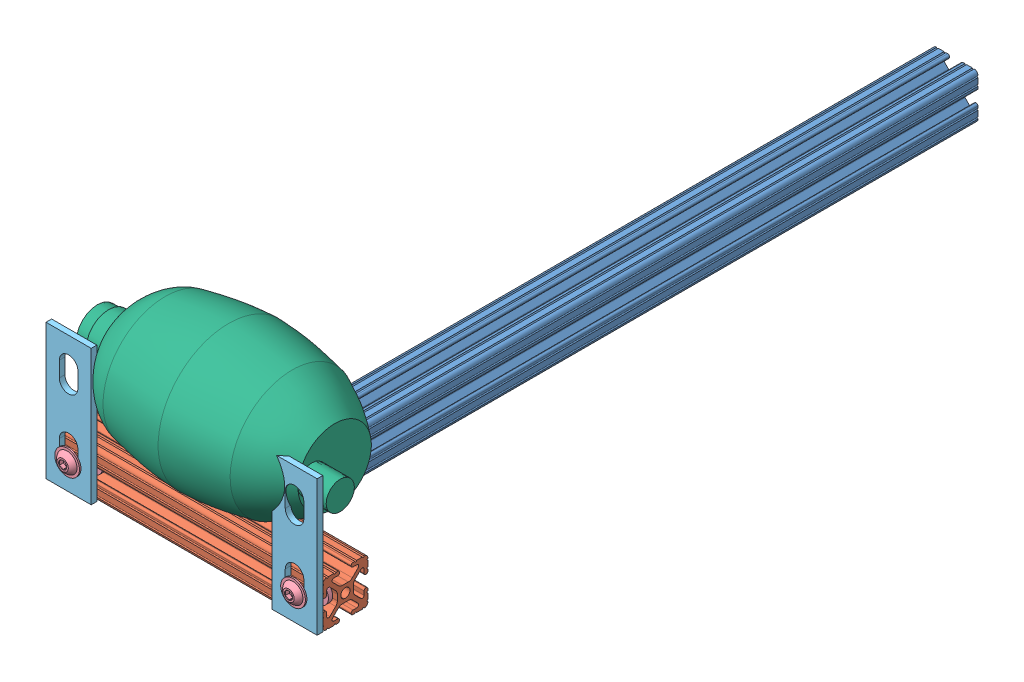
SolidWorks assembly FrameSubAssembly, configuration Default. Lengths in mm.
Overall size (154.3 103.19 450.85).
17 component instances, 6 part files, 17 mates.
Components (placement in the parent):
- 47065T435_ALUMINUM T-SLOTTED FRAMING EXTRUSION cylinder piece-1: 47065T435_ALUMINUM T-SLOTTED FRAMING EXTRUSION cylinder piece [47065T435] at (185.1645 185.311 414.0747) size (25.4 25.4 406.4)
- 47065T435_ALUMINUM T-SLOTTED FRAMING EXTRUSION cylinder piece2-1: 47065T435_ALUMINUM T-SLOTTED FRAMING EXTRUSION cylinder piece2 [47065T435] at (413.7645 185.311 528.3747) x (0 0 -1) z (1 0 0) size (25.4 25.4 152.4)
- BracketSubAssembly-1: BracketSubAssembly [Default] at (199.8275 170.0389 519.1358) x (1 0 0) z (0 1 0) size (33.74 33.74 22.23)
  - 47065T236_ALUMINUM T-SLOTTED FRAMING EXTRUSION-1: 47065T236_ALUMINUM T-SLOTTED FRAMING EXTRUSION [47065T236] at (-1.9629 3.4611 16.8596) size (25.4 25.4 22.23)
  - 47065T142_ALUMINUM T-SLOTTED FRAMING EXTRUSION-3: 47065T142_ALUMINUM T-SLOTTED FRAMING EXTRUSION [47065T142] at (2.8123 16.1611 16.8596) x (0 -1 0) z (0 0 1) size (25.4 16.7 13.87)
  - 47065T142_ALUMINUM T-SLOTTED FRAMING EXTRUSION-4: 47065T142_ALUMINUM T-SLOTTED FRAMING EXTRUSION [47065T142] at (10.7371 8.2363 16.8596) size (25.4 16.7 13.87)
- BracketSubAssembly-2: BracketSubAssembly [Default] at (170.5016 203.7582 519.1358) x (-1 0 0) z (0 -1 0) size (33.74 33.74 22.23)
  - 47065T236_ALUMINUM T-SLOTTED FRAMING EXTRUSION-1: 47065T236_ALUMINUM T-SLOTTED FRAMING EXTRUSION [47065T236] at (-1.9629 3.4611 16.8596) size (25.4 25.4 22.23)
  - 47065T142_ALUMINUM T-SLOTTED FRAMING EXTRUSION-3: 47065T142_ALUMINUM T-SLOTTED FRAMING EXTRUSION [47065T142] at (2.8123 16.1611 16.8596) x (0 -1 0) z (0 0 1) size (25.4 16.7 13.87)
  - 47065T142_ALUMINUM T-SLOTTED FRAMING EXTRUSION-4: 47065T142_ALUMINUM T-SLOTTED FRAMING EXTRUSION [47065T142] at (10.7371 8.2363 16.8596) size (25.4 16.7 13.87)
- BagBracketSubAssembly-1: BagBracketSubAssembly [Default] at (195.5559 169.3719 579.2774) x (0 0 -1) z (1 0 0) size (16.7 76.2 25.4)
  - 2312N340_FLAT-SURFACE MACHINE BRACKET-1: 2312N340_FLAT-SURFACE MACHINE BRACKET [2312N34] at (38.2027 41.3392 53.1086) x (0 1 0) z (0 0 1) size (76.2 3.17 25.4)
  - 47065T142_ALUMINUM T-SLOTTED FRAMING EXTRUSION-1: 47065T142_ALUMINUM T-SLOTTED FRAMING EXTRUSION [47065T142] at (35.0277 17.9839 53.1086) x (0 0 1) z (0 -1 0) size (25.4 16.7 13.87)
- BagBracketSubAssembly-2: BagBracketSubAssembly [Default] at (68.5559 169.3719 579.2774) x (0 0 -1) z (1 0 0) size (16.7 76.2 25.4)
  - 2312N340_FLAT-SURFACE MACHINE BRACKET-1: 2312N340_FLAT-SURFACE MACHINE BRACKET [2312N34] at (38.2027 41.3392 53.1086) x (0 1 0) z (0 0 1) size (76.2 3.17 25.4)
  - 47065T142_ALUMINUM T-SLOTTED FRAMING EXTRUSION-1: 47065T142_ALUMINUM T-SLOTTED FRAMING EXTRUSION [47065T142] at (35.0277 17.9839 53.1086) x (0 0 1) z (0 -1 0) size (25.4 16.7 13.87)
- Bag-2: Bag [Default] at (187.8568 236.111 520.3841) x (0 -1 0) z (1 0 0) size (79.38 79.38 149.22)
Mates (geometry in assembly coordinates):
- Coincident1: coincident aligned: line of 47065T435_ALUMINUM T-SLOTTED FRAMING EXTRUSION cylinder piece-1 through (185.1645 185.311 515.6747) axis (0 0 -1); line of 47065T435_ALUMINUM T-SLOTTED FRAMING EXTRUSION cylinder piece2-1 through (185.1645 185.311 525.798) axis (0 0 -1)
- Distance1: distance = 406.4 mm aligned: plane of 47065T435_ALUMINUM T-SLOTTED FRAMING EXTRUSION cylinder piece2-1 through (718.5645 191.6441 515.6747) normal (0 0 -1); plane of 47065T435_ALUMINUM T-SLOTTED FRAMING EXTRUSION cylinder piece-1 through (178.7481 175.9012 109.2747) normal (0 0 -1)
- Coincident3: coincident anti-aligned: plane of 47065T435_ALUMINUM T-SLOTTED FRAMING EXTRUSION cylinder piece-1 through (197.8645 191.6441 718.8747) normal (1 0 0); plane of BracketSubAssembly-1/47065T236_ALUMINUM T-SLOTTED FRAMING EXTRUSION-1 through (197.8645 198.011 515.6747) normal (-1 0 0)
- Coincident4: coincident anti-aligned: plane of 47065T435_ALUMINUM T-SLOTTED FRAMING EXTRUSION cylinder piece2-1 through (718.5645 191.6441 515.6747) normal (0 0 -1); plane of BracketSubAssembly-1/47065T236_ALUMINUM T-SLOTTED FRAMING EXTRUSION-1 through (223.2645 198.011 515.6747) normal (0 0 1)
- Coincident5: coincident aligned: plane of 47065T435_ALUMINUM T-SLOTTED FRAMING EXTRUSION cylinder piece-1 through (194.715 198.011 718.8747) normal (0 1 0); plane of BracketSubAssembly-1/47065T236_ALUMINUM T-SLOTTED FRAMING EXTRUSION-1 through (197.8645 198.011 495.0499) normal (0 1 0)
- Coincident6: coincident anti-aligned: plane of 47065T435_ALUMINUM T-SLOTTED FRAMING EXTRUSION cylinder piece2-1 through (718.5645 191.6441 515.6747) normal (0 0 -1); plane of BracketSubAssembly-2/47065T236_ALUMINUM T-SLOTTED FRAMING EXTRUSION-1 through (147.0645 175.786 515.6747) normal (0 0 1)
- Coincident8: coincident anti-aligned: plane of 47065T435_ALUMINUM T-SLOTTED FRAMING EXTRUSION cylinder piece-1 through (172.4645 194.8614 718.8747) normal (-1 0 0); plane of BracketSubAssembly-2/47065T236_ALUMINUM T-SLOTTED FRAMING EXTRUSION-1 through (172.4645 175.786 515.6747) normal (1 0 0)
- Coincident9: coincident aligned: plane of 47065T435_ALUMINUM T-SLOTTED FRAMING EXTRUSION cylinder piece-1 through (178.8314 198.011 718.8747) normal (0 1 0); plane of BracketSubAssembly-2/47065T236_ALUMINUM T-SLOTTED FRAMING EXTRUSION-1 through (172.4645 198.011 495.0499) normal (0 1 0)
- Coincident11: coincident anti-aligned: plane of 47065T435_ALUMINUM T-SLOTTED FRAMING EXTRUSION cylinder piece2-1 through (718.5645 194.8614 541.0747) normal (0 0 1); plane of BagBracketSubAssembly-1/2312N340_FLAT-SURFACE MACHINE BRACKET-1 through (248.6645 210.711 541.0747) normal (0 0 -1)
- Coincident12: coincident aligned: plane of 47065T435_ALUMINUM T-SLOTTED FRAMING EXTRUSION cylinder piece2-1 through (718.5645 172.611 537.9251) normal (0 -1 0); plane of BagBracketSubAssembly-1/2312N340_FLAT-SURFACE MACHINE BRACKET-1 through (235.9645 172.611 544.2497) normal (0 -1 0)
- Coincident13: coincident aligned: plane of 47065T435_ALUMINUM T-SLOTTED FRAMING EXTRUSION cylinder piece2-1 through (261.3645 185.311 528.3747) normal (1 0 0); plane of BagBracketSubAssembly-1/2312N340_FLAT-SURFACE MACHINE BRACKET-1 through (261.3645 172.611 544.2497) normal (1 0 0)
- Coincident14: coincident anti-aligned: plane of 47065T435_ALUMINUM T-SLOTTED FRAMING EXTRUSION cylinder piece2-1 through (718.5645 194.8614 541.0747) normal (0 0 1); plane of BagBracketSubAssembly-2/2312N340_FLAT-SURFACE MACHINE BRACKET-1 through (121.6645 210.711 541.0747) normal (0 0 -1)
- Coincident15: coincident aligned: plane of 47065T435_ALUMINUM T-SLOTTED FRAMING EXTRUSION cylinder piece2-1 through (718.5645 172.611 537.9251) normal (0 -1 0); plane of BagBracketSubAssembly-2/2312N340_FLAT-SURFACE MACHINE BRACKET-1 through (108.9645 172.611 544.2497) normal (0 -1 0)
- Coincident16: coincident aligned: plane of 47065T435_ALUMINUM T-SLOTTED FRAMING EXTRUSION cylinder piece2-1 through (108.9645 175.9012 534.7911) normal (-1 0 0); plane of BagBracketSubAssembly-2/2312N340_FLAT-SURFACE MACHINE BRACKET-1 through (108.9645 172.611 544.2497) normal (-1 0 0)
- Distance3: distance = 5.08 mm aligned: plane of BagBracketSubAssembly-2/2312N340_FLAT-SURFACE MACHINE BRACKET-1 through (108.9645 172.611 544.2497) normal (-1 0 0); plane of Bag-2 through (114.0445 224.2048 520.4372) normal (-1 0 0)
- Tangent2: tangent anti-aligned: plane of BagBracketSubAssembly-1/2312N340_FLAT-SURFACE MACHINE BRACKET-1 through (248.6645 210.711 541.0747) normal (0 0 -1); cylinder of Bag-2 through (263.2695 236.111 533.1372) axis (-1 0 0) radius 7.9375
- Distance2: distance = 38.1 mm: cylinder of Bag-2 through (263.2695 236.111 533.1372) axis (-1 0 0) radius 7.9375; plane of 47065T435_ALUMINUM T-SLOTTED FRAMING EXTRUSION cylinder piece2-1 through (718.5645 198.011 534.7078) normal (0 1 0)
